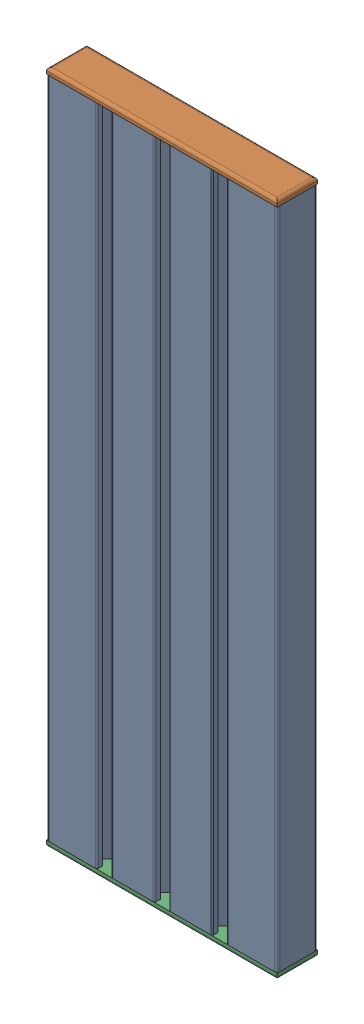
SolidWorks assembly 8cmX23cm Plate with Cap, configuration Default. Lengths in mm.
Overall size (80 234 14).
3 component instances, 2 part files, 6 mates.
Components (placement in the parent):
- 8cmX23cm Plate-1: 8cmX23cm Plate [Default] at (-96.8648 -77.4667 103.7439) size (80 230 14)
- 8cmX23cm Plate Cap-1: 8cmX23cm Plate Cap [Default] at (-16.8648 152.5333 103.7439) x (-1 0 0) z (0 0 1) size (80 8 14)
- 8cmX23cm Plate Cap-2: 8cmX23cm Plate Cap [Default] at (-96.8648 -77.4667 103.7439) size (80 8 14)
Mates (geometry in assembly coordinates):
- Distance1: distance = 0 mm anti-aligned: plane of 8cmX23cm Plate-1 through (-96.8648 152.5333 103.7439) normal (0 1 0); plane of 8cmX23cm Plate Cap-1 through (-16.8648 152.5333 103.7439) normal (0 -1 0)
- Coincident7: coincident aligned: plane of 8cmX23cm Plate-1 through (-16.8648 152.5333 103.7439) normal (1 0 0); plane of 8cmX23cm Plate Cap-1 through (-16.8648 154.5333 103.7439) normal (1 0 0)
- Coincident8: coincident aligned: plane of 8cmX23cm Plate-1 through (-96.8648 152.5333 103.7439) normal (0 0 1); plane of 8cmX23cm Plate Cap-1 through (-16.8648 154.5333 103.7439) normal (0 0 1)
- Coincident9: coincident anti-aligned: plane of 8cmX23cm Plate-1 through (-96.8648 -77.4667 103.7439) normal (0 -1 0); plane of 8cmX23cm Plate Cap-2 through (-96.8648 -77.4667 103.7439) normal (0 1 0)
- Coincident10: coincident aligned: plane of 8cmX23cm Plate-1 through (-16.8648 152.5333 103.7439) normal (1 0 0); plane of 8cmX23cm Plate Cap-2 through (-16.8648 -79.4667 103.7439) normal (1 0 0)
- Coincident11: coincident aligned: plane of 8cmX23cm Plate-1 through (-96.8648 152.5333 103.7439) normal (0 0 1); plane of 8cmX23cm Plate Cap-2 through (-96.8648 -79.4667 103.7439) normal (0 0 1)
